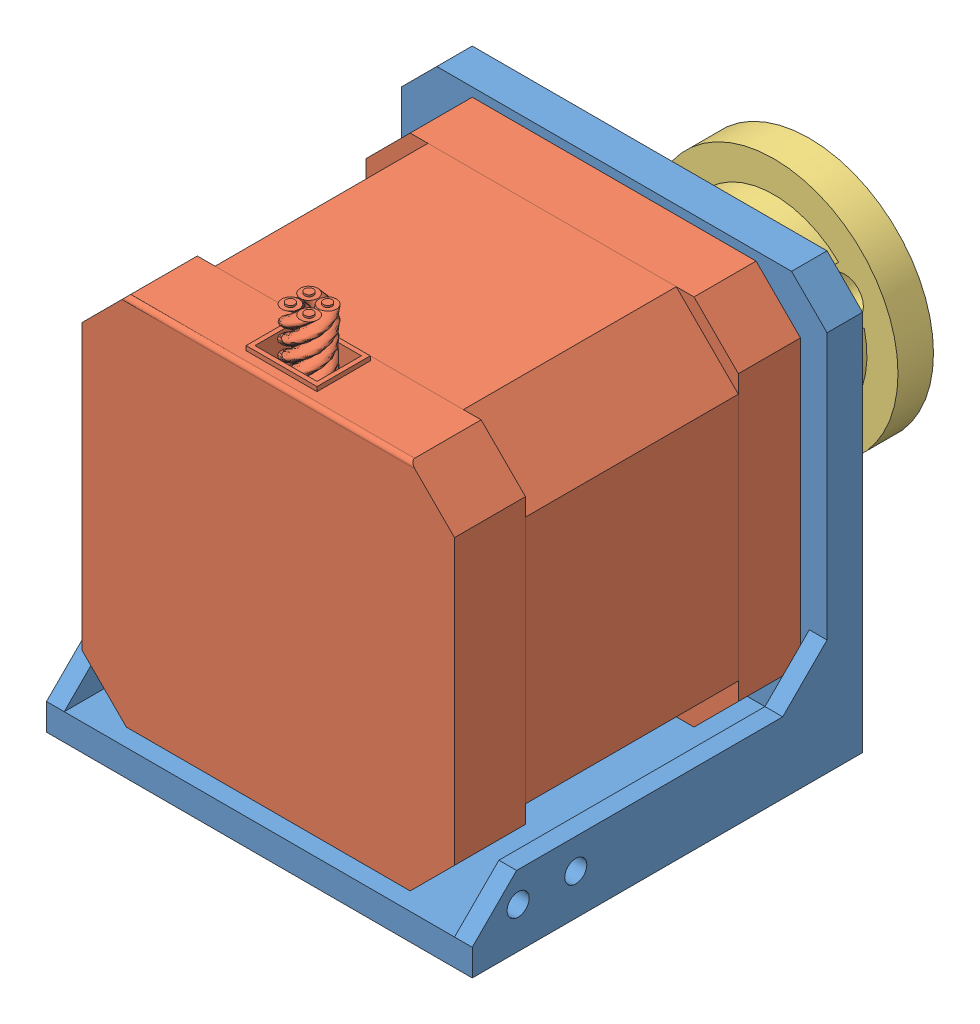
SolidWorks assembly Stepper_Assembly, configuration Standard. Lengths in mm.
Overall size (48 53.25 62).
3 component instances, 3 part files, 5 mates.
Components (placement in the parent):
- Stepper_holder-1: Stepper_holder [Standard] at (-64.8316 -5.4083 0) size (48 49 44)
- nema17-1: nema17 [По умолчанию] at (-85.8316 40.5917 21) x (0 -1 0) z (1 0 0) size (47.25 61 42)
- Wheel_Hub-1: Wheel_Hub [Standard] at (-64.8316 19.5917 -40) size (28 28 12)
Mates (geometry in assembly coordinates):
- Deckungsgleich1: coincident anti-aligned: plane of Stepper_holder-1 through (-88.8316 41.5917 -18) normal (0 0 1); plane of nema17-1 through (-43.8316 40.5917 -18) normal (0 0 -1)
- Konzentrisch1: concentric aligned: circle of Stepper_holder-1; circle of nema17-1
- Konzentrisch2: concentric aligned: circle of nema17-1; circle of Wheel_Hub-1
- Deckungsgleich3: coincident aligned: plane of nema17-1 through (-64.8316 19.5917 -40) normal (0 0 -1); plane of Wheel_Hub-1 through (-64.8316 19.5917 -40) normal (0 0 -1)
- Parallel2: parallel anti-aligned: axis of Wheel_Hub-1 through (-64.8316 22.0917 -32) axis (0 1 0); line of Stepper_holder-1 through (-40.8316 37.5917 -22) axis (0 -1 0)
